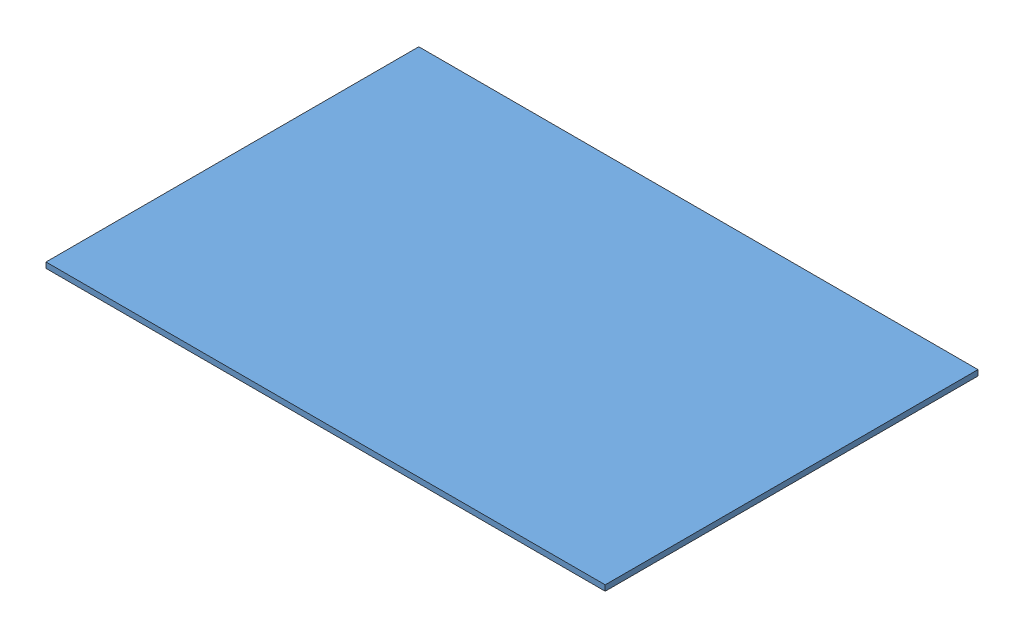
SolidWorks assembly milling-3mm-test, configuration Default. Lengths in mm.
Overall size (300 3 200).
3 component instances, 3 part files, 12 mates.
Components (placement in the parent):
- carbon-stock-3mm-1: carbon-stock-3mm [Default] at origin size (300 3 200)
- battery-stopper-1: battery-stopper [Default] at (-142.1 0 83) x (0 0 1) z (0 1 0) size (31 14.1 3)
- test-joint-1: test-joint [Default] at (-120.6 0 83) x (0 0 1) z (-1 0 0) size (32 3 25)
Mates (geometry in assembly coordinates):
- Coincident1: coincident aligned: plane of carbon-stock-3mm-1 through (0 0 0) normal (0 -1 0); plane of frame-bottom-1 through (-98.3978 0 34.8478) normal (0 -1 0)
- Coincident4: coincident aligned: plane of carbon-stock-3mm-1 through (0 0 0) normal (0 -1 0); plane of frame-bottom-3 through (-85.3054 0 -54.9864) normal (0 -1 0)
- Coincident7: coincident aligned: plane of carbon-stock-3mm-1 through (0 0 0) normal (0 -1 0); plane of frame-bottom-5 through (-72.0249 0 60.8583) normal (0 -1 0)
- Distance3: distance = 1 mm aligned: plane of battery-stopper-1 through (-149 3 83) normal (-1 0 0); plane of carbon-stock-3mm-1 through (-150 3 -100) normal (-1 0 0)
- Coincident10: coincident aligned: plane of carbon-stock-3mm-1 through (0 0 0) normal (0 -1 0); plane of battery-stopper-1 through (-142.1 0 83) normal (0 -1 0)
- Distance8: distance = 1 mm: line of frame-bottom-1 through (-149 3 -29.3043) axis (0 0 1); plane of carbon-stock-3mm-1 through (-150 3 -100) normal (-1 0 0)
- Distance9: distance = 1 mm: line of frame-bottom-1 through (-28.2187 3 99) axis (-1 0 0); plane of carbon-stock-3mm-1 through (-150 3 100) normal (0 0 1)
- Distance11: distance = 3 mm anti-aligned: cylinder of battery-stopper-1 through (-139.5 3 70.9) axis (0 1 0) radius 3.4; plane of frame-bottom-1 through (-86.5984 -132.8669 49.3349) normal (0.631517 0 0.775362)
- Coincident12: coincident aligned: plane of carbon-stock-3mm-1 through (0 0 0) normal (0 -1 0); plane of test-joint-1 through (-120.6 0 83) normal (0 -1 0)
- Distance13: distance = 3 mm anti-aligned: plane of test-joint-1 through (-133.1 3 99) normal (-1 0 0); plane of battery-stopper-1 through (-136.1 3 83) normal (1 0 0)
- Coincident17: coincident aligned: plane of battery-stopper-1 through (-142.1 0 83) normal (0 0 1); plane of test-joint-1 through (-120.6 0 83) normal (0 0 1)
- Distance14: distance = 1 mm aligned: plane of test-joint-1 through (-108.1 3 99) normal (0 0 1); plane of carbon-stock-3mm-1 through (-150 3 100) normal (0 0 1)
